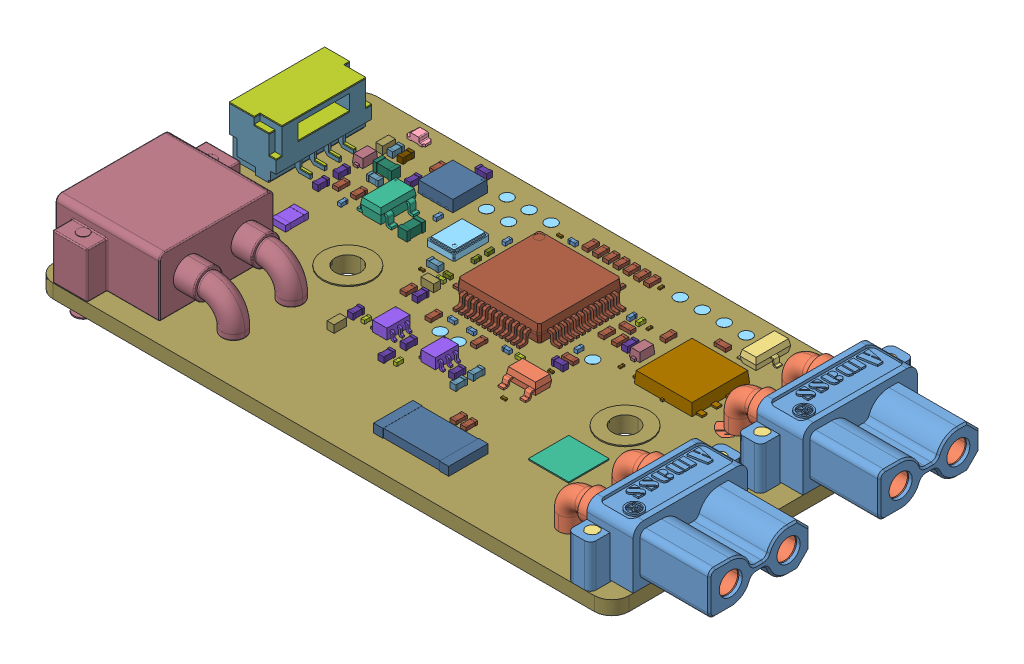
SolidWorks assembly RoboMaster 超级电容管理模块 CM01, configuration 默认. Lengths in mm.
Overall size (56 7.26 28).
114 component instances, 32 part files, 0 mates.
Components (placement in the parent):
- RoboMaster 超级电容管理模块 CM01.stp-1: RoboMaster 超级电容管理模块 CM01.stp [默认] at origin size (56 7.26 28)
  - XT30PW-F_1_2_ASM.stp-1: XT30PW-F_1_2_ASM.stp [默认] at (20.2 3.25 7.35) x (0 0 -1) z (1 0 0) size (13.3 7.16 15.5)
    - XT30PW-F_SJ_1_2.stp-1: XT30PW-F_SJ_1_2.stp [默认] at origin size (13.3 5.16 10)
    - MR30PW-F20__V01_1_2.stp-1: MR30PW-F20__V01_1_2.stp [默认] at (2.5 0 10.5) x (0 0 -1) z (1 0 0) size (15.2 5.9 3)
    - XT30__-_3_____1_2.stp-1: XT30__-_3_____1_2.stp [默认] at (5.5 1.05 1.8) x (0 -1 0) z (0.997757 0 -0.066939) size (5.7 1.1 1.1)
    - XT30__-_3_____1_2.stp-2: XT30__-_3_____1_2.stp [默认] at (-5.5 1.05 1.8) x (0 -1 0) z (0.686322 0 -0.727298) size (5.7 1.1 1.1)
    - MR30PW-F20__V01_1_2.stp-2: MR30PW-F20__V01_1_2.stp [默认] at (-2.5 0 10.5) x (0 0 -1) z (1 0 0) size (15.2 5.9 3)
  - XT30PW-F_1_2_ASM.stp-2: XT30PW-F_1_2_ASM.stp [默认] at (20.2 3.25 -7.35) x (0 0 -1) z (1 0 0) size (13.3 7.16 15.5)
    - XT30PW-F_SJ_1_2.stp-1: XT30PW-F_SJ_1_2.stp [默认] at origin size (13.3 5.16 10)
    - MR30PW-F20__V01_1_2.stp-1: MR30PW-F20__V01_1_2.stp [默认] at (2.5 0 10.5) x (0 0 -1) z (1 0 0) size (15.2 5.9 3)
    - XT30__-_3_____1_2.stp-1: XT30__-_3_____1_2.stp [默认] at (5.5 1.05 1.8) x (0 -1 0) z (0.997757 0 -0.066939) size (5.7 1.1 1.1)
    - XT30__-_3_____1_2.stp-2: XT30__-_3_____1_2.stp [默认] at (-5.5 1.05 1.8) x (0 -1 0) z (0.686322 0 -0.727298) size (5.7 1.1 1.1)
    - MR30PW-F20__V01_1_2.stp-2: MR30PW-F20__V01_1_2.stp [默认] at (-2.5 0 10.5) x (0 0 -1) z (1 0 0) size (15.2 5.9 3)
  - 3D_FQ1702_DZ_SP0001_V1_0428A_20_ASM.stp-1: 3D_FQ1702_DZ_SP0001_V1_0428A_20_ASM.stp [默认] at (-121.9424 -0.6065 227.2175) x (1 0 0) z (0 1 0) size (39.69 24.32 4.46)
    - HOLE_PC4P2DC2P2.stp-1: HOLE_PC4P2DC2P2.stp [默认] at (109.9424 227.2175 1.2065) size (4.2 4.2 0.01)
    - HOLE_PC4P2DC2P2.stp-2: HOLE_PC4P2DC2P2.stp [默认] at (133.9423 227.2175 1.2065) size (4.2 4.2 0.01)
    - TP_C1.stp-1: TP_C1.stp [默认] at (118.8212 226.3394 1.2065) size (1 1 0.01)
    - TP_C1.stp-2: TP_C1.stp [默认] at (113.5634 237.5154 1.2065) size (1 1 0.01)
    - TP_C1.stp-3: TP_C1.stp [默认] at (115.4684 239.2934 1.2065) size (1 1 0.01)
    - TP_C1.stp-4: TP_C1.stp [默认] at (113.5634 239.2934 1.2065) size (1 1 0.01)
    - TP_C1.stp-5: TP_C1.stp [默认] at (132.3594 239.2934 1.2065) size (1 1 0.01)
    - TP_C1.stp-6: TP_C1.stp [默认] at (130.4544 239.2934 1.2065) size (1 1 0.01)
    - TP_C1.stp-7: TP_C1.stp [默认] at (128.5494 239.2934 1.2065) size (1 1 0.01)
    - TP_C1.stp-8: TP_C1.stp [默认] at (126.6444 239.2934 1.2065) size (1 1 0.01)
    - TP_C1.stp-9: TP_C1.stp [默认] at (127.5334 230.8352 1.2065) size (1 1 0.01)
    - TP_C1.stp-10: TP_C1.stp [默认] at (111.6584 239.2934 1.2065) size (1 1 0.01)
    - TP_C1.stp-11: TP_C1.stp [默认] at (111.6584 237.5154 1.2065) size (1 1 0.01)
    - TP_C1.stp-12: TP_C1.stp [默认] at (120.3706 226.3394 1.2065) size (1 1 0.01)
    - QRCODE_3P5X3P5.stp-1: QRCODE_3P5X3P5.stp [默认] at (134.0104 222.2754 1.2065) size (3.5 3.5 0.1)
    - C0201_B.stp-1: C0201_B.stp [默认] at (114.9604 223.7994 1.2065) x (0 1 0) z (0 0 1) size (0.6 0.3 0.3)
    - C0201_B.stp-2: C0201_B.stp [默认] at (119.5324 222.0214 1.2065) x (0 -1 0) z (0 0 1) size (0.6 0.3 0.3)
    - C0201_B.stp-3: C0201_B.stp [默认] at (124.4854 227.6094 1.2065) x (-1 0 0) z (0 0 1) size (0.6 0.3 0.3)
    - C0201_B.stp-4: C0201_B.stp [默认] at (127.0254 235.4834 1.2065) x (0 1 0) z (0 0 1) size (0.6 0.3 0.3)
    - C0201_B.stp-5: C0201_B.stp [默认] at (115.2144 230.0224 1.2065) size (0.6 0.3 0.3)
    - R0805.stp-1: R0805.stp [默认] at (104.1654 227.9904 1.2065) x (0 1 0) z (0 0 1) size (2 1.25 0.5)
    - R0201.stp-1: R0201.stp [默认] at (129.4384 231.4194 1.2065) x (0 -1 0) z (0 0 1) size (0.4 0.2 0.13)
    - R0201.stp-2: R0201.stp [默认] at (116.9924 238.5314 1.2065) size (0.4 0.2 0.13)
    - R0201.stp-3: R0201.stp [默认] at (126.7714 223.9264 1.2065) x (-1 0 0) z (0 0 1) size (0.4 0.2 0.13)
    - R0201.stp-4: R0201.stp [默认] at (125.2474 239.0394 1.2065) x (0 -1 0) z (0 0 1) size (0.4 0.2 0.13)
    - R0201.stp-5: R0201.stp [默认] at (127.7874 235.4834 1.2065) x (0 1 0) z (0 0 1) size (0.4 0.2 0.13)
    - R0201.stp-6: R0201.stp [默认] at (113.5634 230.0224 1.2065) x (-1 0 0) z (0 0 1) size (0.4 0.2 0.13)
    - R0201.stp-7: R0201.stp [默认] at (126.7714 227.9904 1.2065) size (0.4 0.2 0.13)
    - R2512_S.stp-1: R2512_S.stp [默认] at (126.8984 217.4494 1.2065) size (6.5 3.4 0.75)
    - R0402.stp-1: R0402.stp [默认] at (114.5794 227.8634 1.2065) x (0 -1 0) z (0 0 1) size (1 0.5 0.3)
    - R0402.stp-2: R0402.stp [默认] at (132.3594 237.2614 1.2065) x (-1 0 0) z (0 0 1) size (1 0.5 0.3)
    - R0402.stp-3: R0402.stp [默认] at (121.8184 239.0394 1.2065) x (0 1 0) z (0 0 1) size (1 0.5 0.3)
    - R0402.stp-4: R0402.stp [默认] at (129.3114 235.6104 1.2065) x (0 -1 0) z (0 0 1) size (1 0.5 0.3)
    - R0402.stp-5: R0402.stp [默认] at (126.7714 229.6414 1.2065) size (1 0.5 0.3)
    - R0402.stp-6: R0402.stp [默认] at (117.6274 226.9744 1.2065) x (0 1 0) z (0 0 1) size (1 0.5 0.3)
    - R0402.stp-7: R0402.stp [默认] at (121.5644 226.9744 1.2065) x (0 -1 0) z (0 0 1) size (1 0.5 0.3)
    - R0402.stp-8: R0402.stp [默认] at (105.1814 232.9434 1.2065) x (0 -1 0) z (0 0 1) size (1 0.5 0.3)
    - R0402.stp-9: R0402.stp [默认] at (119.1514 239.0394 1.2065) x (0 1 0) z (0 0 1) size (1 0.5 0.3)
    - R0402.stp-10: R0402.stp [默认] at (127.5334 233.1974 1.2065) x (0 1 0) z (0 0 1) size (1 0.5 0.3)
    - R0402.stp-11: R0402.stp [默认] at (120.9294 239.0394 1.2065) x (0 1 0) z (0 0 1) size (1 0.5 0.3)
    - R0402.stp-12: R0402.stp [默认] at (122.7074 239.0394 1.2065) x (0 1 0) z (0 0 1) size (1 0.5 0.3)
    - R0402.stp-13: R0402.stp [默认] at (124.4854 239.0394 1.2065) x (0 -1 0) z (0 0 1) size (1 0.5 0.3)
    - R0402.stp-14: R0402.stp [默认] at (126.8984 234.4674 1.2065) x (-1 0 0) z (0 0 1) size (1 0.5 0.3)
    - R0402.stp-15: R0402.stp [默认] at (123.5964 239.0394 1.2065) x (0 1 0) z (0 0 1) size (1 0.5 0.3)
    - R0402.stp-16: R0402.stp [默认] at (126.3904 233.1974 1.2065) x (0 1 0) z (0 0 1) size (1 0.5 0.3)
    - R0402.stp-17: R0402.stp [默认] at (106.7054 238.2774 1.2065) x (0 1 0) z (0 0 1) size (1 0.5 0.3)
    - R0402.stp-18: R0402.stp [默认] at (120.0404 239.0394 1.2065) x (0 1 0) z (0 0 1) size (1 0.5 0.3)
    - R0402.stp-19: R0402.stp [默认] at (103.7844 232.8164 1.2065) x (0 1 0) z (0 0 1) size (1 0.5 0.3)
    - R0402.stp-20: R0402.stp [默认] at (127.2794 220.3704 1.2065) x (0 1 0) z (0 0 1) size (1 0.5 0.3)
    - R0402.stp-21: R0402.stp [默认] at (126.3904 220.3704 1.2065) x (0 1 0) z (0 0 1) size (1 0.5 0.3)
    - L0402_B.stp-1: L0402_B.stp [默认] at (115.0874 229.2604 1.2065) x (-1 0 0) z (0 0 1) size (1.1 0.6 0.65)
    - L0402_B.stp-2: L0402_B.stp [默认] at (114.0714 222.1484 1.2065) x (0 1 0) z (0 0 1) size (1.1 0.6 0.65)
    - L0402_B.stp-3: L0402_B.stp [默认] at (102.7938 237.6424 1.2065) x (0 1 0) z (0 0 1) size (1.1 0.6 0.65)
    - SOD-523_2-1P2X0P8-0P65.stp-1: SOD-523_2-1P2X0P8-0P65.stp [默认] at (129.4384 233.1974 1.2065) x (0 -1 0) z (0 0 1) size (1.7 0.9 0.7)
    - SOD-523_2-1P2X0P8-0P65.stp-2: SOD-523_2-1P2X0P8-0P65.stp [默认] at (102.9208 235.7374 1.2065) x (0 -1 0) z (0 0 1) size (1.7 0.9 0.7)
    - C0402_B.stp-1: C0402_B.stp [默认] at (113.9444 230.7844 1.2065) x (-1 0 0) z (0 0 1) size (1 0.5 0.5)
    - C0402_B.stp-2: C0402_B.stp [默认] at (103.6574 237.6424 1.2065) x (0 -1 0) z (0 0 1) size (1 0.5 0.5)
    - C0402_B.stp-3: C0402_B.stp [默认] at (123.8504 224.4344 1.2065) x (0 -1 0) z (0 0 1) size (1 0.5 0.5)
    - C0402_B.stp-4: C0402_B.stp [默认] at (104.9274 234.5944 1.2065) x (-1 0 0) z (0 0 1) size (1 0.5 0.5)
    - C0402_B.stp-5: C0402_B.stp [默认] at (123.8504 222.9104 1.2065) x (0 -1 0) z (0 0 1) size (1 0.5 0.5)
    - C0603.stp-1: C0603.stp [默认] at (104.8004 235.7374 1.2065) x (-1 0 0) z (0 0 1) size (1.6 0.8 0.8)
    - C0603.stp-2: C0603.stp [默认] at (110.3884 232.3084 1.2065) x (0 -1 0) z (0 0 1) size (1.6 0.8 0.8)
    - C0201_A.stp-1: C0201_A.stp [默认] at (115.2144 230.6574 1.2065) x (-1 0 0) z (0 0 1) size (0.6 0.3 0.3)
    - C0201_A.stp-2: C0201_A.stp [默认] at (115.2144 233.0704 1.2065) x (0 1 0) z (0 0 1) size (0.6 0.3 0.3)
    - C0201_A.stp-3: C0201_A.stp [默认] at (115.2144 234.2134 1.2065) x (0 -1 0) z (0 0 1) size (0.6 0.3 0.3)
    - C0402.stp-1: C0402.stp [默认] at (118.6434 221.8944 1.2065) x (0 -1 0) z (0 0 1) size (1 0.5 0.5)
    - C0402.stp-2: C0402.stp [默认] at (106.7054 236.1184 1.2065) x (0 -1 0) z (0 0 1) size (1 0.5 0.5)
    - C0402.stp-3: C0402.stp [默认] at (109.1184 239.8014 1.2065) x (-1 0 0) z (0 0 1) size (1 0.5 0.5)
    - C0402.stp-4: C0402.stp [默认] at (122.9614 223.6724 1.2065) x (0 1 0) z (0 0 1) size (1 0.5 0.5)
    - C0402.stp-5: C0402.stp [默认] at (114.0714 223.7994 1.2065) x (0 1 0) z (0 0 1) size (1 0.5 0.5)
    - C0402.stp-6: C0402.stp [默认] at (126.7714 228.7524 1.2065) x (-1 0 0) z (0 0 1) size (1 0.5 0.5)
    - C0402.stp-7: C0402.stp [默认] at (118.6434 223.7994 1.2065) x (0 1 0) z (0 0 1) size (1 0.5 0.5)
    - C0402.stp-8: C0402.stp [默认] at (128.4224 233.1974 1.2065) x (0 1 0) z (0 0 1) size (1 0.5 0.5)
    - C0402.stp-9: C0402.stp [默认] at (102.9208 233.7054 1.2065) x (0 -1 0) z (0 0 1) size (1 0.5 0.5)
    - C0402.stp-10: C0402.stp [默认] at (102.9208 231.9274 1.2065) x (0 -1 0) z (0 0 1) size (1 0.5 0.5)
    - C0402.stp-11: C0402.stp [默认] at (115.5954 227.8634 1.2065) x (0 1 0) z (0 0 1) size (1 0.5 0.5)
    - C0402_D.stp-1: C0402_D.stp [默认] at (104.5464 237.6424 1.2065) x (0 -1 0) z (0 0 1) size (1 0.5 0.5)
    - C0201.stp-1: C0201.stp [默认] at (126.3904 230.7844 1.2065) x (0 1 0) z (0 0 1) size (0.6 0.3 0.3)
    - C0201.stp-2: C0201.stp [默认] at (110.3884 234.5944 1.2065) x (0 1 0) z (0 0 1) size (0.6 0.3 0.3)
    - C0201.stp-3: C0201.stp [默认] at (105.1814 231.5464 1.2065) x (0 -1 0) z (0 0 1) size (0.6 0.3 0.3)
    - C0201.stp-4: C0201.stp [默认] at (118.1354 238.5314 1.2065) size (0.6 0.3 0.3)
    - C0201.stp-5: C0201.stp [默认] at (115.2144 235.7374 1.2065) x (0 -1 0) z (0 0 1) size (0.6 0.3 0.3)
    - C0201.stp-6: C0201.stp [默认] at (123.3424 227.6094 1.2065) x (-1 0 0) z (0 0 1) size (0.6 0.3 0.3)
    - C0201.stp-7: C0201.stp [默认] at (120.4214 227.4824 1.2065) size (0.6 0.3 0.3)
    - C0201.stp-8: C0201.stp [默认] at (118.7704 227.4824 1.2065) size (0.6 0.3 0.3)
    - C0201.stp-9: C0201.stp [默认] at (126.2634 235.4834 1.2065) x (0 -1 0) z (0 0 1) size (0.6 0.3 0.3)
    - SOT-23_3-1P9-3X1P4-1P2.stp-1: SOT-23_3-1P9-3X1P4-1P2.stp [默认] at (126.7714 226.0854 1.2065) size (2.5 3 1.1)
    - SOT-23_3-1P9-3X1P4-1P11.stp-1: SOT-23_3-1P9-3X1P4-1P11.stp [默认] at (135.0264 238.2774 1.2065) x (0 -1 0) z (0 0 1) size (3 2.5 1.1)
    - LED_4-1P6X0P8-0P7.stp-1: LED_4-1P6X0P8-0P7.stp [默认] at (103.6574 239.6744 1.2065) size (1.6 0.8 0.6)
    - X3225.stp-1: X3225.stp [默认] at (113.1062 233.6038 1.2065) x (0 -1 0) z (0 0 1) size (3.08 2.38 0.71)
    - SOT-23_5-0P95-3P05X1P75-1P45.stp-1: SOT-23_5-0P95-3P05X1P75-1P45.stp [默认] at (107.7214 232.9434 1.2065) size (3 3.05 1.45)
    - GH_4-1P25-8P25X4P05-4P35_H.stp-1: GH_4-1P25-8P25X4P05-4P35_H.stp [默认] at (98.9675 234.0927 1.2065) x (0 -1 0) z (0 0 1) size (8.25 4.85 4.35)
    - SOT-363_6-0P65-2P25X1P35-1P1.stp-1: SOT-363_6-0P65-2P25X1P35-1P1.stp [默认] at (116.7384 224.1804 1.2065) x (0 -1 0) z (0 0 1) size (2 2.1 1)
    - SOT-363_6-0P65-2P25X1P35-1P1.stp-2: SOT-363_6-0P65-2P25X1P35-1P1.stp [默认] at (121.0564 224.0534 1.2065) x (0 -1 0) z (0 0 1) size (2 2.1 1)
    - VSON_8-1P27-5X5-1.stp-1: VSON_8-1P27-5X5-1.stp [默认] at (133.6294 233.3244 1.2065) size (6 5.3 1.01)
    - DFN_9-0P65-3X3-1-H2P4X1P65.stp-1: DFN_9-0P65-3X3-1-H2P4X1P65.stp [默认] at (108.9914 237.2614 1.2065) x (-1 0 0) z (0 0 1) size (3 3.03 1)
    - QFP_48-0P5-7P2X7P2-1P6.stp-1: QFP_48-0P5-7P2X7P2-1P6.stp [默认] at (120.777 232.9688 1.2065) x (0 -1 0) z (0 0 1) size (9.2 9.2 1.6)
  - DRB_1_1.stp-1: DRB_1_1.stp [默认] at origin size (49.85 1.4 28)
  - USER_LIBRARY-XT30PW-M.stp-1: USER_LIBRARY-XT30PW-M.stp [默认] at (-20.5 0.6 7.35) x (1 0 0) z (0 1 0) size (14.45 13.3 7.1)
  - SM04B-GHS-TB.stp-1: SM04B-GHS-TB.stp [默认] at (-20.95 0.7 -2.75) x (0 0 1) z (-1 0 0) size (8.25 4.35 4.85)
